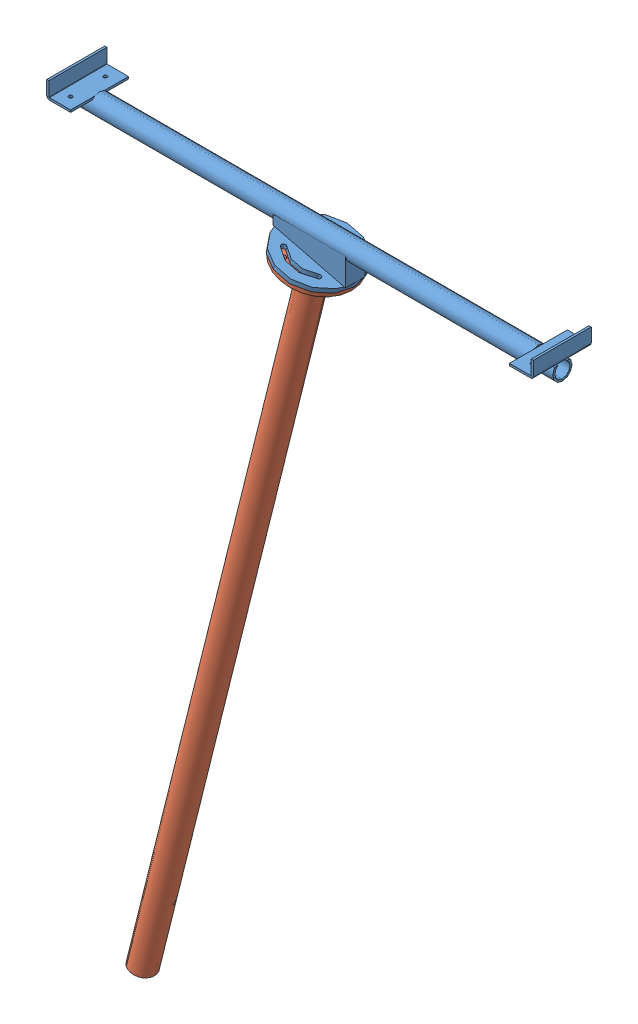
SolidWorks assembly Assem_Flange, configuration Default. Lengths in mm.
Overall size (672.2 1048.39 121.2).
3 component instances, 3 part files, 4 mates.
Components (placement in the parent):
- Across Mount_flange-1: Across Mount_flange [Default<As Machined>] at (218.7173 344.0353 541.8428) size (672.2 75.9 103.06)
- Panel-1: Panel [Default] at (535.9211 355.5453 867.0992) x (-0.999041 0 -0.043792) z (-0.043792 0 0.999041) size (665 30 650) (hidden)
- Stand_flange-1: Stand_flange [Slot] at (217.1811 312.1086 541.8428) x (0.234498 -0.058467 0.970357) z (0.941533 -0.234751 -0.241676) size (100 1000 100)
Mates (geometry in assembly coordinates):
- Coincident1: coincident anti-aligned: plane of Across Mount_flange-1 through (521.7173 355.5453 581.8428) normal (0 1 0); plane of Panel-1 through (535.9211 355.5453 867.0992) normal (0 -1 0)
- Concentric2: concentric anti-aligned: cylinder of Across Mount_flange-1 through (537.7173 355.5453 517.8428) axis (0 1 0) radius 2.5273; cylinder of Panel-1 through (537.7173 355.5453 517.8428) axis (0 -1 0) radius 2.5273
- Coincident3: coincident anti-aligned: plane of Across Mount_flange-1 through (217.1811 312.1086 541.8428) normal (-0.241922 -0.970296 0); plane of Stand_flange-1 through (217.1811 312.1086 541.8428) normal (0.241922 0.970296 0)
- Concentric3: concentric aligned: cylinder of Across Mount_flange-1 through (217.1811 312.1086 541.8428) axis (0.241922 0.970296 0) radius 51.5307; cylinder of Stand_flange-1 through (215.6449 305.9472 541.8428) axis (0.241922 0.970296 0) radius 50
